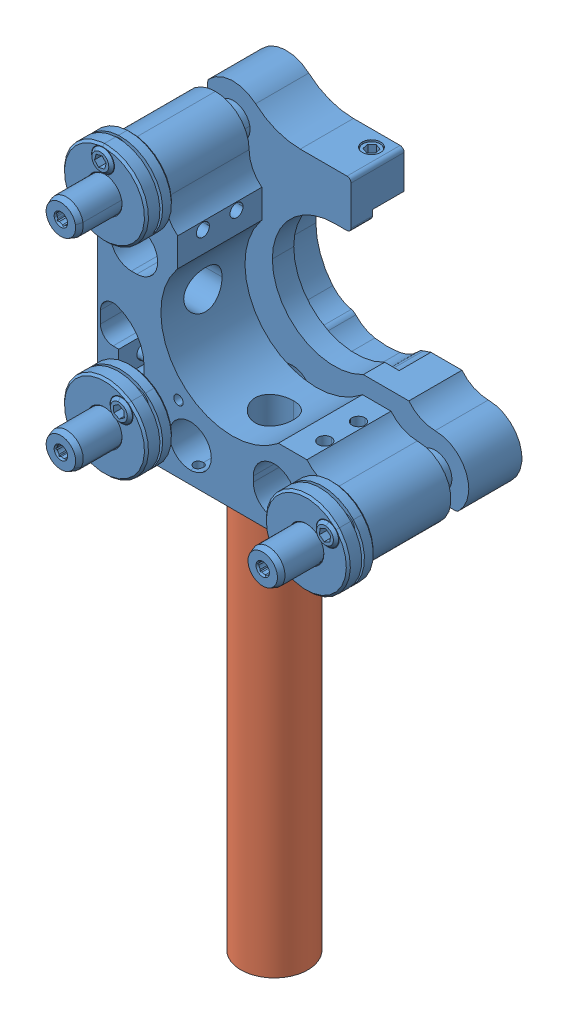
SolidWorks assembly Mirror holder assembled, configuration Default. Lengths in mm.
Overall size (53.98 128.56 42.58).
2 component instances, 2 part files, 3 mates.
Components (placement in the parent):
- Newport-U100-A3H.stp-1: Newport-U100-A3H.stp [Default] at (-172.1028 -102.6999 -107.2719) size (53.98 53.98 42.58)
- Mirror shaft-1: Mirror shaft [Default] at (-78.0363 -104.445 43.1749) x (-0.381849 0 -0.924225) z (0.924225 0 -0.381849) size (12.68 76.17 12.68)
Mates (geometry in assembly coordinates):
- Concentric1: concentric anti-aligned: circle of Newport-U100-A3H.stp-1; cylinder of Mirror shaft-1 through (-78.0363 -28.275 43.1749) axis (0 -1 0) radius 6.34
- Coincident1: coincident anti-aligned: plane of Newport-U100-A3H.stp-1 through (-103.4363 -28.275 35.2374) normal (0 -1 0); plane of Mirror shaft-1 through (-78.0363 -28.275 43.1749) normal (0 1 0)
- Lock1: lock: unknown of Newport-U100-A3H.stp-1; unknown of Mirror shaft-1
